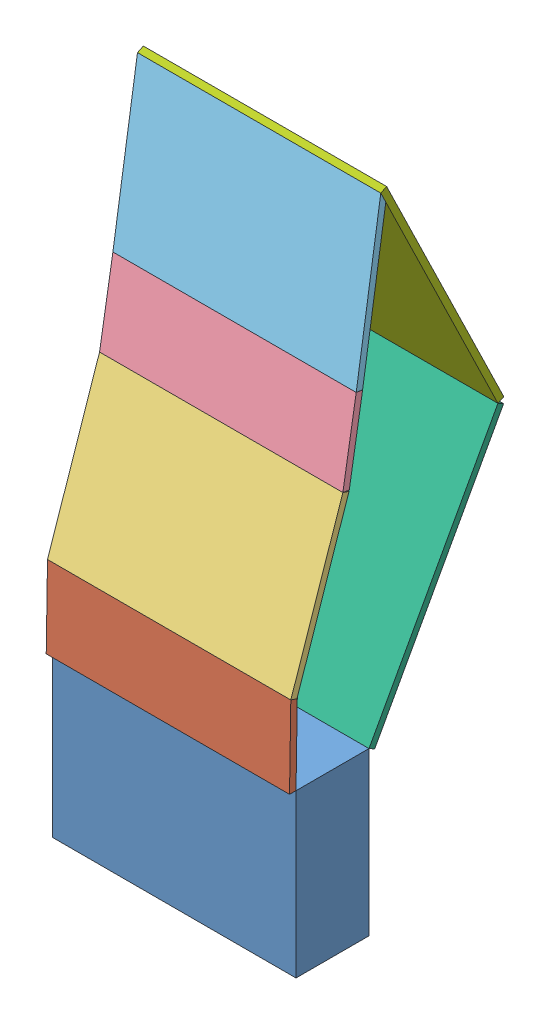
SolidWorks assembly Compliant Assembly, configuration Default. Lengths in mm.
Overall size (150 394.68 132.1).
7 component instances, 7 part files, 13 mates.
Components (placement in the parent):
- E-1: E [Default] at (-57.6684 39.1997 150.6179) size (150 100 45)
- Aa-2: Aa [Default] at (92.3316 139.1997 150.6179) x (0 0.999874 -0.015894) z (0 0.015894 0.999874) size (50 150 4)
- Ab-2: Ab [Default] at (92.3316 187.9734 150.0343) x (0 0.947114 -0.320896) z (0 0.320896 0.947114) size (100 150 4)
- Ba-1: Ba [Default] at (-57.6684 283.9684 121.7331) x (0 0.986387 -0.164438) z (0 -0.164438 -0.986387) size (70 150 8)
- Bb-1: Bb [Default] at (92.3316 332.6814 109.5575) x (0 0.988442 -0.151597) z (0 0.151597 0.988442) size (100 150 4)
- C-1: C [Default] at (92.3316 137.2724 102.1129) x (0 0.876268 -0.481824) z (1 0 0) size (165 4 150)
- D-1: D [Default] at (-57.6684 432.132 98.3515) x (1 0 0) z (0 0.89908 0.437785) size (150 4 165)
Mates (geometry in assembly coordinates):
- Coincident1: coincident aligned: line of E-1 through (-57.6684 139.1997 150.6179) axis (1 0 0); line of Aa-2 through (-57.6684 139.1997 150.6179) axis (1 0 0)
- Coincident2: coincident aligned: plane of E-1 through (-57.6684 139.1997 150.6179) normal (-1 0 0); plane of Aa-2 through (-57.6684 139.2633 154.6174) normal (-1 0 0)
- Coincident3: coincident anti-aligned: line of Aa-2 through (92.3316 189.257 153.8227) axis (-1 0 0); line of Ab-2 through (-57.6684 189.257 153.8227) axis (1 0 0)
- Coincident4: coincident aligned: plane of E-1 through (-57.6684 139.1997 150.6179) normal (-1 0 0); plane of Ab-2 through (-57.6684 189.257 153.8227) normal (-1 0 0)
- Coincident5: coincident aligned: line of Ab-2 through (92.3316 283.9684 121.7331) axis (-1 0 0); line of Ba-1 through (92.3316 283.9684 121.7331) axis (-1 0 0)
- Coincident7: coincident aligned: plane of E-1 through (-57.6684 139.1997 150.6179) normal (-1 0 0); plane of Ba-1 through (-57.6684 283.3107 117.7876) normal (-1 0 0)
- Coincident22: coincident aligned: line of Ba-1 through (-57.6684 333.2878 113.5112) axis (1 0 0); line of Bb-1 through (-57.6684 333.2878 113.5112) axis (1 0 0)
- Coincident23: coincident aligned: plane of E-1 through (-57.6684 139.1997 150.6179) normal (-1 0 0); plane of Bb-1 through (-57.6684 333.2878 113.5112) normal (-1 0 0)
- Coincident28: coincident anti-aligned: line of E-1 through (92.3316 139.1997 105.6179) axis (-1 0 0); line of C-1 through (-57.6684 139.1997 105.6179) axis (1 0 0)
- Coincident29: coincident aligned: plane of E-1 through (-57.6684 139.1997 150.6179) normal (-1 0 0); plane of C-1 through (-57.6684 139.1997 105.6179) normal (-1 0 0)
- Coincident30: coincident aligned: line of C-1 through (92.3316 283.7839 26.1169) axis (-1 0 0); line of D-1 through (92.3316 283.7839 26.1169) axis (-1 0 0)
- Coincident31: coincident aligned: plane of E-1 through (-57.6684 139.1997 150.6179) normal (-1 0 0); plane of D-1 through (-57.6684 433.8832 94.7552) normal (-1 0 0)
- Coincident32: coincident anti-aligned: line of Bb-1 through (92.3316 432.132 98.3515) axis (-1 0 0); line of D-1 through (-57.6684 432.132 98.3515) axis (1 0 0)
